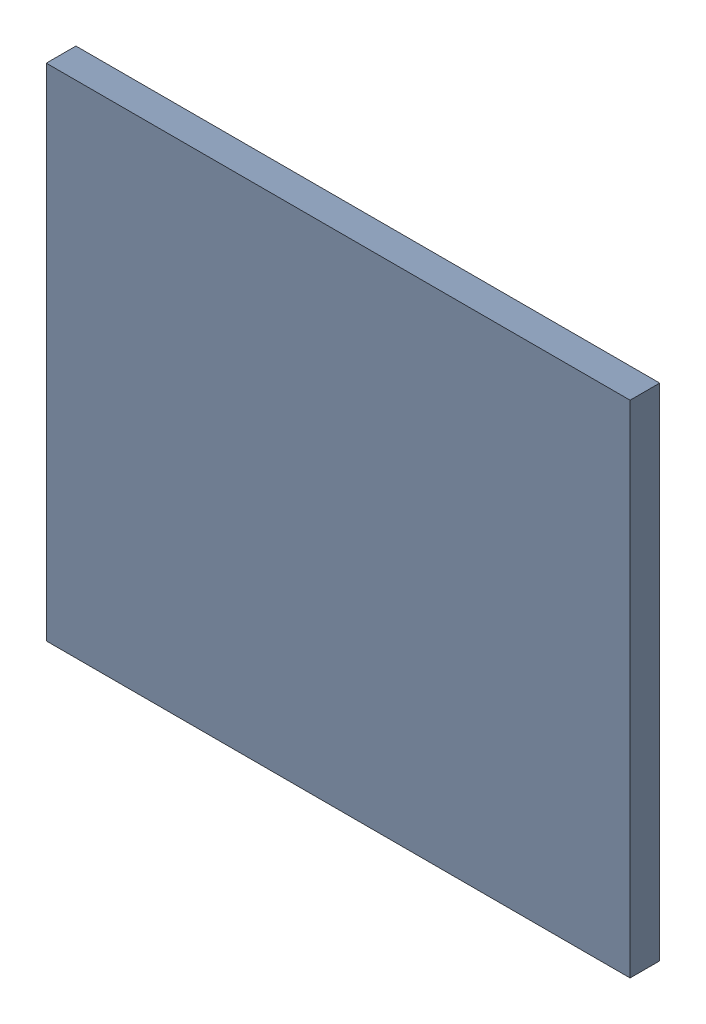
SolidWorks assembly Pad R1-2(28.05mm,40mm) on Top Layer, configuration Predeterminado. Lengths in mm.
Overall size (0.7 0.6 0.04).
2 component instances, 1 part files, 0 mates.
Components (placement in the parent):
- Pad R1-2(28.05mm,40mm) on Top Layer-1-1: Pad R1-2(28.05mm,40mm) on Top Layer-1 [Predeterminado] at (-68.317 -44.187 -0.0457) size (0.7 0.6 0.04)
  - Pad R1-2(28.05mm,40mm) on Top Layer-Part-1-1: Pad R1-2(28.05mm,40mm) on Top Layer-Part-1 [Predeterminado] at origin size (0.7 0.6 0.04)
